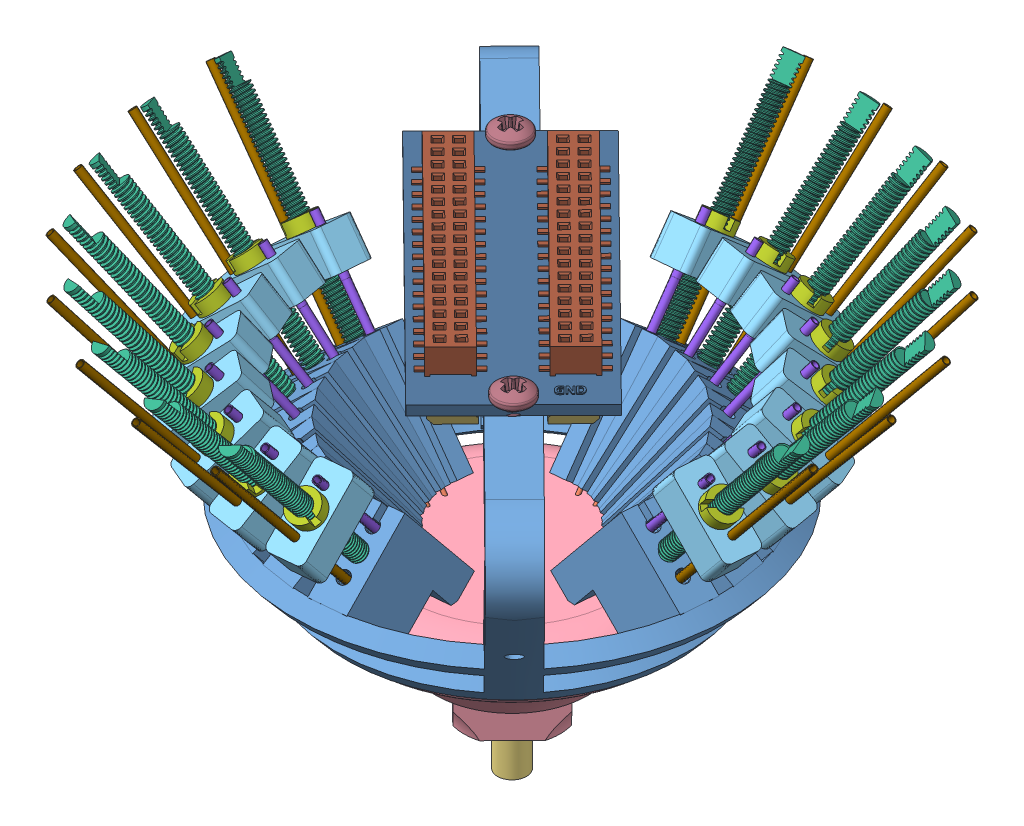
SolidWorks assembly DriveAssembly-Omnetics, configuration Default. Lengths in mm.
Overall size (57.17 40.07 57.14).
123 component instances, 13 part files, 92 mates.
Components (placement in the parent):
- drive_circle_16-1: drive_circle_16 [Default] at (0.6579 7.146 2.7452) x (0.996757 0 0.080473) z (-0.080473 0 0.996757) size (47.61 33.72 39.95)
- 30g Tubing Curved-1: 30g Tubing Curved [Default] at (-0.3006 6 2.6678) x (0.996757 0 0.080473) z (-0.080473 0 0.996757) size (13.26 23.81 0.32)
- 30g Tubing Curved-5: 30g Tubing Curved [Default] at (-0.29 6 2.9067) x (0.985792 0 -0.167972) z (0.167972 0 0.985792) size (13.26 23.81 0.32)
- 30g Tubing Curved-13: 30g Tubing Curved [Default] at (-0.2209 6 3.1356) x (0.91386 0 -0.406029) z (0.406029 0 0.91386) size (13.26 23.81 0.32)
- 30g Tubing Curved-14: 30g Tubing Curved [Default] at (-0.0973 6 3.3404) x (0.78541 0 -0.618976) z (0.618976 0 0.78541) size (13.26 23.81 0.32)
- 30g Tubing Curved-15: 30g Tubing Curved [Default] at (0.0729 6 3.5084) x (0.608386 0 -0.793641) z (0.793641 0 0.608386) size (13.26 23.81 0.32)
- 30g Tubing Curved-16: 30g Tubing Curved [Default] at (0.2793 6 3.6291) x (0.393737 0 -0.919223) z (0.919223 0 0.393737) size (13.26 23.81 0.32)
- 30g Tubing Curved-17: 30g Tubing Curved [Default] at (0.5091 6 3.6952) x (0.154736 0 -0.987956) z (0.987956 0 0.154736) size (13.26 23.81 0.32)
- 30g Tubing Curved-18: 30g Tubing Curved [Default] at (0.7481 6 3.7026) x (-0.093834 0 -0.995588) z (0.995588 0 -0.093834) size (13.26 23.81 0.32)
- 30g Tubing Curved-27: 30g Tubing Curved [Default] at (1.6164 6 2.8226) x (-0.996757 0 -0.080473) z (0.080473 0 -0.996757) size (13.26 23.81 0.32)
- 30g Tubing Curved-28: 30g Tubing Curved [Default] at (1.6059 6 2.5837) x (-0.985792 0 0.167972) z (-0.167972 0 -0.985792) size (13.26 23.81 0.32)
- 30g Tubing Curved-29: 30g Tubing Curved [Default] at (1.5367 6 2.3548) x (-0.91386 0 0.406029) z (-0.406029 0 -0.91386) size (13.26 23.81 0.32)
- 30g Tubing Curved-30: 30g Tubing Curved [Default] at (1.4132 6 2.15) x (-0.78541 0 0.618976) z (-0.618976 0 -0.78541) size (13.26 23.81 0.32)
- 30g Tubing Curved-31: 30g Tubing Curved [Default] at (1.2429 6 1.982) x (-0.608386 0 0.793641) z (-0.793641 0 -0.608386) size (13.26 23.81 0.32)
- 30g Tubing Curved-34: 30g Tubing Curved [Default] at (1.0365 6 1.8613) x (-0.393737 0 0.919223) z (-0.919223 0 -0.393737) size (13.26 23.81 0.32)
- 30g Tubing Curved-35: 30g Tubing Curved [Default] at (0.8067 6 1.7952) x (-0.154736 0 0.987956) z (-0.987956 0 -0.154736) size (13.26 23.81 0.32)
- 30g Tubing Curved-36: 30g Tubing Curved [Default] at (0.5677 6 1.7878) x (0.093834 0 0.995588) z (-0.995588 0 0.093834) size (13.26 23.81 0.32)
- MainCanula-1: MainCanula [Default] at (0.6579 0 2.7452) x (-0.437751 0 0.899096) z (-0.899096 0 -0.437751) size (2.41 8 2.41)
- AcrylicFill-1: AcrylicFill [Default] at (0.6579 2.4564 2.7452) x (0.711833 0 0.702349) z (-0.702349 0 0.711833) size (25 12 25)
- Shuttle Assembly-18: Shuttle Assembly [Default] at (17.6138 21.248 9.6542) x (-0.76356 0.642788 -0.061646) z (0.080473 0 -0.996757) size (6.5 25.22 3.31)
  - Shuttle-1: Shuttle [Default] at (2.5582 1.9761 5.5221) size (6.5 3 3)
  - Threaded Rod 25mm-1: Threaded Rod 25mm [Default] at (2.5582 -8.5786 5.5221) x (0.813094 0 0.582132) z (-0.582132 0 0.813094) size (1.64 25.22 1.64)
  - Grooved Nut-1: Grooved Nut [Default] at (2.5582 1.9761 5.5221) x (0.414361 0 -0.910113) z (0.910113 0 0.414361) size (2.5 4 2.5)
  - 23g Tubing 13mm-1: 23g Tubing 13mm [Default] at (4.3082 -7.0239 5.5221) size (0.64 13 0.64)
  - 23g Tubing 25mm-1: 23g Tubing 25mm [Default] at (0.8082 -8.5786 5.5221) size (0.62 25 0.62)
- Shuttle Assembly-19: Shuttle Assembly [Default] at (18.7944 21.248 5.2566) x (-0.75516 0.642788 0.128674) z (-0.167972 0 -0.985792) size (6.5 25.22 3.31)
  - Shuttle-1: Shuttle [Default] at (2.5582 1.9761 5.5221) size (6.5 3 3)
  - Threaded Rod 25mm-1: Threaded Rod 25mm [Default] at (2.5582 -8.5786 5.5221) x (0.813094 0 0.582132) z (-0.582132 0 0.813094) size (1.64 25.22 1.64)
  - Grooved Nut-1: Grooved Nut [Default] at (2.5582 1.9761 5.5221) x (0.414361 0 -0.910113) z (0.910113 0 0.414361) size (2.5 4 2.5)
  - 23g Tubing 13mm-1: 23g Tubing 13mm [Default] at (4.3082 -7.0239 5.5221) size (0.64 13 0.64)
  - 23g Tubing 25mm-1: 23g Tubing 25mm [Default] at (0.8082 -8.5786 5.5221) size (0.62 25 0.62)
- Shuttle Assembly-20: Shuttle Assembly [Default] at (18.8532 21.248 0.7036) x (-0.700057 0.642788 0.311037) z (-0.406029 0 -0.91386) size (6.5 25.22 3.31)
  - Shuttle-1: Shuttle [Default] at (2.5582 1.9761 5.5221) size (6.5 3 3)
  - Threaded Rod 25mm-1: Threaded Rod 25mm [Default] at (2.5582 -8.5786 5.5221) x (0.813094 0 0.582132) z (-0.582132 0 0.813094) size (1.64 25.22 1.64)
  - Grooved Nut-1: Grooved Nut [Default] at (2.5582 1.9761 5.5221) x (0.414361 0 -0.910113) z (0.910113 0 0.414361) size (2.5 4 2.5)
  - 23g Tubing 13mm-1: 23g Tubing 13mm [Default] at (4.3082 -7.0239 5.5221) size (0.64 13 0.64)
  - 23g Tubing 25mm-1: 23g Tubing 25mm [Default] at (0.8082 -8.5786 5.5221) size (0.62 25 0.62)
- Shuttle Assembly-21: Shuttle Assembly [Default] at (17.7868 21.248 -3.7231) x (-0.601659 0.642788 0.474163) z (-0.618976 0 -0.78541) size (6.5 25.22 3.31)
  - Shuttle-1: Shuttle [Default] at (2.5582 1.9761 5.5221) size (6.5 3 3)
  - Threaded Rod 25mm-1: Threaded Rod 25mm [Default] at (2.5582 -8.5786 5.5221) x (0.813094 0 0.582132) z (-0.582132 0 0.813094) size (1.64 25.22 1.64)
  - Grooved Nut-1: Grooved Nut [Default] at (2.5582 1.9761 5.5221) x (0.414361 0 -0.910113) z (0.910113 0 0.414361) size (2.5 4 2.5)
  - 23g Tubing 13mm-1: 23g Tubing 13mm [Default] at (4.3082 -7.0239 5.5221) size (0.64 13 0.64)
  - 23g Tubing 25mm-1: 23g Tubing 25mm [Default] at (0.8082 -8.5786 5.5221) size (0.62 25 0.62)
- Shuttle Assembly-22: Shuttle Assembly [Default] at (15.6611 21.248 -7.7497) x (-0.466051 0.642788 0.607964) z (-0.793641 0 -0.608386) size (6.5 25.22 3.31)
  - Shuttle-1: Shuttle [Default] at (2.5582 1.9761 5.5221) size (6.5 3 3)
  - Threaded Rod 25mm-1: Threaded Rod 25mm [Default] at (2.5582 -8.5786 5.5221) x (0.813094 0 0.582132) z (-0.582132 0 0.813094) size (1.64 25.22 1.64)
  - Grooved Nut-1: Grooved Nut [Default] at (2.5582 1.9761 5.5221) x (0.414361 0 -0.910113) z (0.910113 0 0.414361) size (2.5 4 2.5)
  - 23g Tubing 13mm-1: 23g Tubing 13mm [Default] at (4.3082 -7.0239 5.5221) size (0.64 13 0.64)
  - 23g Tubing 25mm-1: 23g Tubing 25mm [Default] at (0.8082 -8.5786 5.5221) size (0.62 25 0.62)
- Shuttle Assembly-23: Shuttle Assembly [Default] at (12.6074 21.248 -11.1273) x (-0.30162 0.642788 0.704166) z (-0.919223 0 -0.393737) size (6.5 25.22 3.31)
  - Shuttle-1: Shuttle [Default] at (2.5582 1.9761 5.5221) size (6.5 3 3)
  - Threaded Rod 25mm-1: Threaded Rod 25mm [Default] at (2.5582 -8.5786 5.5221) x (0.813094 0 0.582132) z (-0.582132 0 0.813094) size (1.64 25.22 1.64)
  - Grooved Nut-1: Grooved Nut [Default] at (2.5582 1.9761 5.5221) x (0.414361 0 -0.910113) z (0.910113 0 0.414361) size (2.5 4 2.5)
  - 23g Tubing 13mm-1: 23g Tubing 13mm [Default] at (4.3082 -7.0239 5.5221) size (0.64 13 0.64)
  - 23g Tubing 25mm-1: 23g Tubing 25mm [Default] at (0.8082 -8.5786 5.5221) size (0.62 25 0.62)
- Shuttle Assembly-24: Shuttle Assembly [Default] at (8.8148 21.248 -13.647) x (-0.118535 0.642788 0.756818) z (-0.987956 0 -0.154736) size (6.5 25.22 3.31)
  - Shuttle-1: Shuttle [Default] at (2.5582 1.9761 5.5221) size (6.5 3 3)
  - Threaded Rod 25mm-1: Threaded Rod 25mm [Default] at (2.5582 -8.5786 5.5221) x (0.813094 0 0.582132) z (-0.582132 0 0.813094) size (1.64 25.22 1.64)
  - Grooved Nut-1: Grooved Nut [Default] at (2.5582 1.9761 5.5221) x (0.414361 0 -0.910113) z (0.910113 0 0.414361) size (2.5 4 2.5)
  - 23g Tubing 13mm-1: 23g Tubing 13mm [Default] at (4.3082 -7.0239 5.5221) size (0.64 13 0.64)
  - 23g Tubing 25mm-1: 23g Tubing 25mm [Default] at (0.8082 -8.5786 5.5221) size (0.62 25 0.62)
- Shuttle Assembly-25: Shuttle Assembly [Default] at (4.5176 21.248 -15.1528) x (0.071881 0.642788 0.762665) z (-0.995588 0 0.093834) size (6.5 25.22 3.31)
  - Shuttle-1: Shuttle [Default] at (2.5582 1.9761 5.5221) size (6.5 3 3)
  - Threaded Rod 25mm-1: Threaded Rod 25mm [Default] at (2.5582 -8.5786 5.5221) x (0.813094 0 0.582132) z (-0.582132 0 0.813094) size (1.64 25.22 1.64)
  - Grooved Nut-1: Grooved Nut [Default] at (2.5582 1.9761 5.5221) x (0.414361 0 -0.910113) z (0.910113 0 0.414361) size (2.5 4 2.5)
  - 23g Tubing 13mm-1: 23g Tubing 13mm [Default] at (4.3082 -7.0239 5.5221) size (0.64 13 0.64)
  - 23g Tubing 25mm-1: 23g Tubing 25mm [Default] at (0.8082 -8.5786 5.5221) size (0.62 25 0.62)
- Shuttle Assembly-26: Shuttle Assembly [Default] at (-16.298 21.248 -4.1638) x (0.76356 0.642788 0.061646) z (-0.080473 0 0.996757) size (6.5 25.22 3.31)
  - Shuttle-1: Shuttle [Default] at (2.5582 1.9761 5.5221) size (6.5 3 3)
  - Threaded Rod 25mm-1: Threaded Rod 25mm [Default] at (2.5582 -8.5786 5.5221) x (0.813094 0 0.582132) z (-0.582132 0 0.813094) size (1.64 25.22 1.64)
  - Grooved Nut-1: Grooved Nut [Default] at (2.5582 1.9761 5.5221) x (0.414361 0 -0.910113) z (0.910113 0 0.414361) size (2.5 4 2.5)
  - 23g Tubing 13mm-1: 23g Tubing 13mm [Default] at (4.3082 -7.0239 5.5221) size (0.64 13 0.64)
  - 23g Tubing 25mm-1: 23g Tubing 25mm [Default] at (0.8082 -8.5786 5.5221) size (0.62 25 0.62)
- Shuttle Assembly-27: Shuttle Assembly [Default] at (-17.4785 21.248 0.2338) x (0.75516 0.642788 -0.128674) z (0.167972 0 0.985792) size (6.5 25.22 3.31)
  - Shuttle-1: Shuttle [Default] at (2.5582 1.9761 5.5221) size (6.5 3 3)
  - Threaded Rod 25mm-1: Threaded Rod 25mm [Default] at (2.5582 -8.5786 5.5221) x (0.813094 0 0.582132) z (-0.582132 0 0.813094) size (1.64 25.22 1.64)
  - Grooved Nut-1: Grooved Nut [Default] at (2.5582 1.9761 5.5221) x (0.414361 0 -0.910113) z (0.910113 0 0.414361) size (2.5 4 2.5)
  - 23g Tubing 13mm-1: 23g Tubing 13mm [Default] at (4.3082 -7.0239 5.5221) size (0.64 13 0.64)
  - 23g Tubing 25mm-1: 23g Tubing 25mm [Default] at (0.8082 -8.5786 5.5221) size (0.62 25 0.62)
- Shuttle Assembly-28: Shuttle Assembly [Default] at (-17.5374 21.248 4.7868) x (0.700057 0.642788 -0.311037) z (0.406029 0 0.91386) size (6.5 25.22 3.31)
  - Shuttle-1: Shuttle [Default] at (2.5582 1.9761 5.5221) size (6.5 3 3)
  - Threaded Rod 25mm-1: Threaded Rod 25mm [Default] at (2.5582 -8.5786 5.5221) x (0.813094 0 0.582132) z (-0.582132 0 0.813094) size (1.64 25.22 1.64)
  - Grooved Nut-1: Grooved Nut [Default] at (2.5582 1.9761 5.5221) x (0.414361 0 -0.910113) z (0.910113 0 0.414361) size (2.5 4 2.5)
  - 23g Tubing 13mm-1: 23g Tubing 13mm [Default] at (4.3082 -7.0239 5.5221) size (0.64 13 0.64)
  - 23g Tubing 25mm-1: 23g Tubing 25mm [Default] at (0.8082 -8.5786 5.5221) size (0.62 25 0.62)
- Shuttle Assembly-29: Shuttle Assembly [Default] at (-16.471 21.248 9.2134) x (0.601659 0.642788 -0.474163) z (0.618976 0 0.78541) size (6.5 25.22 3.31)
  - Shuttle-1: Shuttle [Default] at (2.5582 1.9761 5.5221) size (6.5 3 3)
  - Threaded Rod 25mm-1: Threaded Rod 25mm [Default] at (2.5582 -8.5786 5.5221) x (0.813094 0 0.582132) z (-0.582132 0 0.813094) size (1.64 25.22 1.64)
  - Grooved Nut-1: Grooved Nut [Default] at (2.5582 1.9761 5.5221) x (0.414361 0 -0.910113) z (0.910113 0 0.414361) size (2.5 4 2.5)
  - 23g Tubing 13mm-1: 23g Tubing 13mm [Default] at (4.3082 -7.0239 5.5221) size (0.64 13 0.64)
  - 23g Tubing 25mm-1: 23g Tubing 25mm [Default] at (0.8082 -8.5786 5.5221) size (0.62 25 0.62)
- Shuttle Assembly-30: Shuttle Assembly [Default] at (-14.3452 21.248 13.2401) x (0.466051 0.642788 -0.607964) z (0.793641 0 0.608386) size (6.5 25.22 3.31)
  - Shuttle-1: Shuttle [Default] at (2.5582 1.9761 5.5221) size (6.5 3 3)
  - Threaded Rod 25mm-1: Threaded Rod 25mm [Default] at (2.5582 -8.5786 5.5221) x (0.813094 0 0.582132) z (-0.582132 0 0.813094) size (1.64 25.22 1.64)
  - Grooved Nut-1: Grooved Nut [Default] at (2.5582 1.9761 5.5221) x (0.414361 0 -0.910113) z (0.910113 0 0.414361) size (2.5 4 2.5)
  - 23g Tubing 13mm-1: 23g Tubing 13mm [Default] at (4.3082 -7.0239 5.5221) size (0.64 13 0.64)
  - 23g Tubing 25mm-1: 23g Tubing 25mm [Default] at (0.8082 -8.5786 5.5221) size (0.62 25 0.62)
- Shuttle Assembly-32: Shuttle Assembly [Default] at (-11.2916 21.248 16.6177) x (0.30162 0.642788 -0.704166) z (0.919223 0 0.393737) size (6.5 25.22 3.31)
  - Shuttle-1: Shuttle [Default] at (2.5582 1.9761 5.5221) size (6.5 3 3)
  - Threaded Rod 25mm-1: Threaded Rod 25mm [Default] at (2.5582 -8.5786 5.5221) x (0.813094 0 0.582132) z (-0.582132 0 0.813094) size (1.64 25.22 1.64)
  - Grooved Nut-1: Grooved Nut [Default] at (2.5582 1.9761 5.5221) x (0.414361 0 -0.910113) z (0.910113 0 0.414361) size (2.5 4 2.5)
  - 23g Tubing 13mm-1: 23g Tubing 13mm [Default] at (4.3082 -7.0239 5.5221) size (0.64 13 0.64)
  - 23g Tubing 25mm-1: 23g Tubing 25mm [Default] at (0.8082 -8.5786 5.5221) size (0.62 25 0.62)
- Shuttle Assembly-33: Shuttle Assembly [Default] at (-7.4989 21.248 19.1374) x (0.118535 0.642788 -0.756818) z (0.987956 0 0.154736) size (6.5 25.22 3.31)
  - Shuttle-1: Shuttle [Default] at (2.5582 1.9761 5.5221) size (6.5 3 3)
  - Threaded Rod 25mm-1: Threaded Rod 25mm [Default] at (2.5582 -8.5786 5.5221) x (0.813094 0 0.582132) z (-0.582132 0 0.813094) size (1.64 25.22 1.64)
  - Grooved Nut-1: Grooved Nut [Default] at (2.5582 1.9761 5.5221) x (0.414361 0 -0.910113) z (0.910113 0 0.414361) size (2.5 4 2.5)
  - 23g Tubing 13mm-1: 23g Tubing 13mm [Default] at (4.3082 -7.0239 5.5221) size (0.64 13 0.64)
  - 23g Tubing 25mm-1: 23g Tubing 25mm [Default] at (0.8082 -8.5786 5.5221) size (0.62 25 0.62)
- Shuttle Assembly-34: Shuttle Assembly [Default] at (-3.2018 21.248 20.6432) x (-0.071881 0.642788 -0.762665) z (0.995588 0 -0.093834) size (6.5 25.22 3.31)
  - Shuttle-1: Shuttle [Default] at (2.5582 1.9761 5.5221) size (6.5 3 3)
  - Threaded Rod 25mm-1: Threaded Rod 25mm [Default] at (2.5582 -8.5786 5.5221) x (0.813094 0 0.582132) z (-0.582132 0 0.813094) size (1.64 25.22 1.64)
  - Grooved Nut-1: Grooved Nut [Default] at (2.5582 1.9761 5.5221) x (0.414361 0 -0.910113) z (0.910113 0 0.414361) size (2.5 4 2.5)
  - 23g Tubing 13mm-1: 23g Tubing 13mm [Default] at (4.3082 -7.0239 5.5221) size (0.64 13 0.64)
  - 23g Tubing 25mm-1: 23g Tubing 25mm [Default] at (0.8082 -8.5786 5.5221) size (0.62 25 0.62)
- EIB_millmax-1: EIB_millmax [Default] at (0.6579 33.2883 2.7452) x (0.711833 0 0.702349) z (-0.702349 0 0.711833) size (27.94 8.65 12.7)
  - EIB_millmax_PCB-1: EIB_millmax_PCB [Default] at origin size (27.94 0.9 12.7)
  - Samtec-CLP-117-02-L-D-1: Samtec-CLP-117-02-L-D [LEAD STYLE2PINS17PLATINGLROWD] at (0.2159 0.927 3.691) size (22.02 4.09 4.6)
  - Samtec-CLP-117-02-L-D-3: Samtec-CLP-117-02-L-D [LEAD STYLE2PINS17PLATINGLROWD] at (0.2159 0.927 -3.691) size (22.02 4.09 4.6)
  - Samtec-CLP-116-02-L-DH-1: Samtec-CLP-116-02-L-DH [LEAD STYLE2PINS16PLATINGLROWDH] at (-0.4191 -1.7145 -2.04) x (1 0 0) z (0 1 0) size (20.75 4.57 4.32)
  - Samtec-CLP-116-02-L-DH-2: Samtec-CLP-116-02-L-DH [LEAD STYLE2PINS16PLATINGLROWDH] at (-0.4191 -1.7145 2.04) x (-1 0 0) z (0 1 0) size (20.75 4.57 4.32)
- McMasterCarr_0-80_91772A052-1: McMasterCarr_0-80_91772A052 [91772A052] at (-8.8344 30.9133 -6.6206) x (1 0 0) z (0 1 0) size (2.95 2.95 6.38)
- McMasterCarr_0-80_91772A052-2: McMasterCarr_0-80_91772A052 [91772A052] at (10.1502 30.9133 12.111) x (1 0 0) z (0 1 0) size (2.95 2.95 6.38)
Mates (geometry in assembly coordinates):
- Concentric1: concentric aligned: circle of drive_circle_16-1; circle of 30g Tubing Curved-1
- Concentric5: concentric aligned: circle of 30g Tubing Curved-5; circle of drive_circle_16-1
- Concentric6: concentric aligned: circle of 30g Tubing Curved-13; circle of drive_circle_16-1
- Concentric7: concentric aligned: circle of 30g Tubing Curved-14; circle of drive_circle_16-1
- Concentric8: concentric aligned: circle of 30g Tubing Curved-15; circle of drive_circle_16-1
- Concentric9: concentric aligned: circle of 30g Tubing Curved-16; circle of drive_circle_16-1
- Concentric10: concentric aligned: circle of 30g Tubing Curved-17; circle of drive_circle_16-1
- Concentric11: concentric aligned: circle of 30g Tubing Curved-18; circle of drive_circle_16-1
- Parallel1: parallel anti-aligned: plane of 30g Tubing Curved-5 through (-0.0929 -2 2.8731) normal (0 -1 0); plane of assembly through (0 0 0) normal (0 1 0)
- Parallel2: parallel anti-aligned: plane of 30g Tubing Curved-1 through (-0.1012 -2 2.6839) normal (0 -1 0); plane of assembly through (0 0 0) normal (0 1 0)
- Parallel3: parallel anti-aligned: plane of 30g Tubing Curved-18 through (0.7294 -2 3.5035) normal (0 -1 0); plane of assembly through (0 0 0) normal (0 1 0)
- Parallel4: parallel anti-aligned: plane of 30g Tubing Curved-17 through (0.5401 -2 3.4976) normal (0 -1 0); plane of assembly through (0 0 0) normal (0 1 0)
- Parallel5: parallel anti-aligned: plane of 30g Tubing Curved-16 through (0.358 -2 3.4453) normal (0 -1 0); plane of assembly through (0 0 0) normal (0 1 0)
- Parallel6: parallel anti-aligned: plane of 30g Tubing Curved-15 through (0.1946 -2 3.3496) normal (0 -1 0); plane of assembly through (0 0 0) normal (0 1 0)
- Parallel7: parallel anti-aligned: plane of 30g Tubing Curved-14 through (0.0597 -2 3.2166) normal (0 -1 0); plane of assembly through (0 0 0) normal (0 1 0)
- Parallel8: parallel anti-aligned: plane of 30g Tubing Curved-13 through (-0.0381 -2 3.0544) normal (0 -1 0); plane of assembly through (0 0 0) normal (0 1 0)
- Distance9: distance = 0 mm aligned: plane of 30g Tubing Curved-1 through (-0.1012 -2 2.6839) normal (0 -1 0); plane of MainCanula-1 through (0.6579 -2 2.7452) normal (0 -1 0)
- Concentric12: concentric aligned: line of drive_circle_16-1 through (0.6579 7.146 2.7452) axis (0 1 0); circle of MainCanula-1
- Parallel11: parallel anti-aligned: plane of MainCanula-1 through (0.6579 6 2.7452) normal (0 1 0); plane of AcrylicFill-1 through (0.6579 2.4564 2.7452) normal (0 -1 0)
- Concentric13: concentric aligned: circle of AcrylicFill-1; circle of MainCanula-1
- StabilizerAndDriveConcentric: concentric aligned: circle of drive_circle_16-1; circle of Shuttle Assembly-18/23g Tubing 25mm-1
- BrassNutAndDriveConcentric: concentric anti-aligned: circle of drive_circle_16-1; circle of Shuttle Assembly-18/Grooved Nut-1
- ShuttleHeight: distance = 7 mm aligned: plane of Shuttle Assembly-18/Shuttle-1 through (19.2931 26.7043 4.2497) normal (0.640703 0.766044 0.051727); plane of drive_circle_16-1 through (12.4473 23.4311 2.1921) normal (0.640703 0.766044 0.051727)
- Concentric36: concentric aligned: circle of Shuttle Assembly-19/23g Tubing 25mm-1; circle of drive_circle_16-1
- Concentric37: concentric anti-aligned: circle of Shuttle Assembly-19/Grooved Nut-1; circle of drive_circle_16-1
- Distance11: distance = 7 mm aligned: plane of Shuttle Assembly-19/Shuttle-1 through (19.0881 26.7043 -0.3952) normal (0.633655 0.766044 -0.10797); plane of drive_circle_16-1 through (11.9463 23.4311 -0.6999) normal (0.633655 0.766044 -0.10797)
- Concentric38: concentric aligned: circle of Shuttle Assembly-20/23g Tubing 25mm-1; circle of drive_circle_16-1
- Concentric39: concentric anti-aligned: circle of Shuttle Assembly-20/Grooved Nut-1; circle of drive_circle_16-1
- Distance12: distance = 7 mm aligned: plane of Shuttle Assembly-20/Shuttle-1 through (17.7433 26.7043 -4.8459) normal (0.587418 0.766044 -0.260991); plane of drive_circle_16-1 through (10.7471 23.4311 -3.3788) normal (0.587418 0.766044 -0.260991)
- Concentric40: concentric aligned: circle of drive_circle_16-1; circle of Shuttle Assembly-21/23g Tubing 25mm-1
- Concentric41: concentric anti-aligned: circle of drive_circle_16-1; circle of Shuttle Assembly-21/Grooved Nut-1
- Distance13: distance = 7 mm aligned: plane of Shuttle Assembly-21/Shuttle-1 through (15.3418 26.7043 -8.8271) normal (0.504852 0.766044 -0.39787); plane of drive_circle_16-1 through (8.924 23.4311 -5.6791) normal (0.504852 0.766044 -0.39787)
- Concentric42: concentric aligned: circle of drive_circle_16-1; circle of Shuttle Assembly-22/23g Tubing 25mm-1
- Concentric43: concentric anti-aligned: circle of drive_circle_16-1; circle of Shuttle Assembly-22/Grooved Nut-1
- Distance14: distance = 7 mm aligned: plane of Shuttle Assembly-22/Shuttle-1 through (12.0322 26.7043 -12.0926) normal (0.391063 0.766044 -0.510143); plane of drive_circle_16-1 through (6.5896 23.4311 -7.4583) normal (0.391063 0.766044 -0.510143)
- Concentric44: concentric aligned: circle of drive_circle_16-1; circle of Shuttle Assembly-23/23g Tubing 25mm-1
- Concentric45: concentric anti-aligned: circle of drive_circle_16-1; circle of Shuttle Assembly-23/Grooved Nut-1
- Distance15: distance = 7 mm aligned: plane of Shuttle Assembly-23/Shuttle-1 through (8.0192 26.7043 -14.4405) normal (0.253089 0.766044 -0.590865); plane of drive_circle_16-1 through (3.8884 23.4311 -8.6065) normal (0.253089 0.766044 -0.590865)
- Concentric46: concentric aligned: circle of drive_circle_16-1; circle of Shuttle Assembly-24/23g Tubing 25mm-1
- Concentric47: concentric anti-aligned: circle of drive_circle_16-1; circle of Shuttle Assembly-24/Grooved Nut-1
- Distance16: distance = 7 mm aligned: plane of Shuttle Assembly-24/Shuttle-1 through (3.5508 26.7043 -15.7255) normal (0.099463 0.766044 -0.635046); plane of drive_circle_16-1 through (0.9874 23.4311 -9.0526) normal (0.099463 0.766044 -0.635046)
- Concentric48: concentric aligned: circle of drive_circle_16-1; circle of Shuttle Assembly-25/23g Tubing 25mm-1
- Concentric49: concentric anti-aligned: circle of drive_circle_16-1; circle of Shuttle Assembly-25/Grooved Nut-1
- Distance17: distance = 7 mm aligned: plane of Shuttle Assembly-25/Shuttle-1 through (-1.0964 26.7043 -15.8682) normal (-0.060315 0.766044 -0.639952); plane of drive_circle_16-1 through (-1.934 23.4311 -8.7691) normal (-0.060315 0.766044 -0.639952)
- Concentric50: concentric anti-aligned: circle of drive_circle_16-1; circle of Shuttle Assembly-26/23g Tubing 25mm-1
- Concentric51: concentric aligned: circle of drive_circle_16-1; circle of Shuttle Assembly-26/Grooved Nut-1
- Distance18: distance = 7 mm aligned: plane of Shuttle Assembly-26/Shuttle-1 through (-17.9773 26.7043 1.2407) normal (-0.640703 0.766044 -0.051727); plane of drive_circle_16-1 through (-10.8901 23.4311 0.308) normal (-0.640703 0.766044 -0.051727)
- Concentric52: concentric anti-aligned: circle of drive_circle_16-1; circle of Shuttle Assembly-27/23g Tubing 25mm-1
- Concentric53: concentric aligned: circle of drive_circle_16-1; circle of Shuttle Assembly-27/Grooved Nut-1
- Distance19: distance = 7 mm aligned: plane of Shuttle Assembly-27/Shuttle-1 through (-17.7723 26.7043 5.8856) normal (-0.633655 0.766044 0.10797); plane of drive_circle_16-1 through (-11.1344 23.4311 3.2329) normal (-0.633655 0.766044 0.10797)
- Concentric54: concentric anti-aligned: circle of drive_circle_16-1; circle of Shuttle Assembly-28/23g Tubing 25mm-1
- Concentric55: concentric aligned: circle of drive_circle_16-1; circle of Shuttle Assembly-28/Grooved Nut-1
- Distance20: distance = 7 mm aligned: plane of Shuttle Assembly-28/Shuttle-1 through (-16.4275 26.7043 10.3363) normal (-0.587418 0.766044 0.260991); plane of drive_circle_16-1 through (-10.6494 23.4311 6.1277) normal (-0.587418 0.766044 0.260991)
- Concentric56: concentric anti-aligned: circle of drive_circle_16-1; circle of Shuttle Assembly-29/23g Tubing 25mm-1
- Concentric57: concentric aligned: circle of drive_circle_16-1; circle of Shuttle Assembly-29/Grooved Nut-1
- Distance21: distance = 7 mm aligned: plane of Shuttle Assembly-29/Shuttle-1 through (-14.026 26.7043 14.3175) normal (-0.504852 0.766044 0.39787); plane of drive_circle_16-1 through (-9.4651 23.4311 8.8132) normal (-0.504852 0.766044 0.39787)
- Concentric58: concentric anti-aligned: circle of drive_circle_16-1; circle of Shuttle Assembly-30/23g Tubing 25mm-1
- Concentric59: concentric aligned: circle of drive_circle_16-1; circle of Shuttle Assembly-30/Grooved Nut-1
- Distance22: distance = 7 mm aligned: plane of Shuttle Assembly-30/Shuttle-1 through (-10.7164 26.7043 17.583) normal (-0.391063 0.766044 0.510143); plane of drive_circle_16-1 through (-7.6547 23.4311 11.1235) normal (-0.391063 0.766044 0.510143)
- Concentric61: concentric anti-aligned: circle of Shuttle Assembly-32/23g Tubing 25mm-1; circle of drive_circle_16-1
- Concentric62: concentric aligned: circle of Shuttle Assembly-32/Grooved Nut-1; circle of drive_circle_16-1
- Distance23: distance = 7 mm aligned: plane of Shuttle Assembly-32/Shuttle-1 through (-6.7033 26.7043 19.9309) normal (-0.253089 0.766044 0.590865); plane of drive_circle_16-1 through (-5.3303 23.4311 12.9157) normal (-0.253089 0.766044 0.590865)
- Concentric63: concentric anti-aligned: circle of drive_circle_16-1; circle of Shuttle Assembly-33/23g Tubing 25mm-1
- Concentric64: concentric aligned: circle of Shuttle Assembly-33/Grooved Nut-1; circle of drive_circle_16-1
- Distance24: distance = 7 mm aligned: plane of Shuttle Assembly-33/Shuttle-1 through (-2.235 26.7043 21.2159) normal (-0.099463 0.766044 0.635046); plane of drive_circle_16-1 through (-2.6355 23.4311 14.0788) normal (-0.099463 0.766044 0.635046)
- Concentric65: concentric anti-aligned: circle of drive_circle_16-1; circle of Shuttle Assembly-34/23g Tubing 25mm-1
- Concentric66: concentric aligned: circle of drive_circle_16-1; circle of Shuttle Assembly-34/Grooved Nut-1
- Distance25: distance = 7 mm aligned: plane of Shuttle Assembly-34/Shuttle-1 through (2.4122 26.7043 21.3586) normal (0.060315 0.766044 0.639952); plane of drive_circle_16-1 through (0.263 23.4311 14.541) normal (0.060315 0.766044 0.639952)
- Concentric67: concentric anti-aligned: circle of drive_circle_16-1; circle of 30g Tubing Curved-27
- Parallel12: parallel anti-aligned: plane of 30g Tubing Curved-27 through (1.4171 -2 2.8065) normal (0 -1 0); plane of assembly through (0 0 0) normal (0 1 0)
- Concentric68: concentric anti-aligned: circle of drive_circle_16-1; circle of 30g Tubing Curved-28
- Parallel13: parallel anti-aligned: plane of 30g Tubing Curved-28 through (1.4087 -2 2.6173) normal (0 -1 0); plane of assembly through (0 0 0) normal (0 1 0)
- Concentric69: concentric anti-aligned: circle of drive_circle_16-1; circle of 30g Tubing Curved-29
- Parallel14: parallel anti-aligned: plane of 30g Tubing Curved-29 through (1.3539 -2 2.436) normal (0 -1 0); plane of assembly through (0 0 0) normal (0 1 0)
- Concentric70: concentric anti-aligned: circle of drive_circle_16-1; circle of 30g Tubing Curved-30
- Parallel15: parallel anti-aligned: plane of 30g Tubing Curved-30 through (1.2561 -2 2.2738) normal (0 -1 0); plane of assembly through (0 0 0) normal (0 1 0)
- Concentric71: concentric anti-aligned: circle of drive_circle_16-1; circle of 30g Tubing Curved-31
- Parallel16: parallel anti-aligned: plane of 30g Tubing Curved-31 through (1.1213 -2 2.1408) normal (0 -1 0); plane of assembly through (0 0 0) normal (0 1 0)
- Parallel19: parallel anti-aligned: plane of 30g Tubing Curved-34 through (0.9578 -2 2.0451) normal (0 -1 0); plane of assembly through (0 0 0) normal (0 1 0)
- Concentric73: concentric anti-aligned: circle of drive_circle_16-1; circle of 30g Tubing Curved-34
- Concentric74: concentric anti-aligned: circle of drive_circle_16-1; circle of 30g Tubing Curved-35
- Parallel20: parallel anti-aligned: plane of 30g Tubing Curved-35 through (0.7758 -2 1.9928) normal (0 -1 0); plane of assembly through (0 0 0) normal (0 1 0)
- Concentric75: concentric anti-aligned: circle of drive_circle_16-1; circle of 30g Tubing Curved-36
- Parallel21: parallel anti-aligned: plane of 30g Tubing Curved-36 through (0.5864 -2 1.9869) normal (0 -1 0); plane of assembly through (0 0 0) normal (0 1 0)
- Concentric77: concentric aligned: circle of drive_circle_16-1; circle of EIB_millmax-1/EIB_millmax_PCB-1
- Concentric79: concentric aligned: circle of drive_circle_16-1; circle of EIB_millmax-1/EIB_millmax_PCB-1
- Coincident34: coincident anti-aligned: plane of drive_circle_16-1 through (-22.6906 33.2883 -17.8338) normal (0 1 0); plane of EIB_millmax-1/EIB_millmax_PCB-1 through (0.6579 33.2883 2.7452) normal (0 -1 0)
- Concentric80: concentric anti-aligned: circle of EIB_millmax-1/EIB_millmax_PCB-1; circle of McMasterCarr_0-80_91772A052-1
- Coincident35: coincident anti-aligned: plane of EIB_millmax-1/EIB_millmax_PCB-1 through (0.6579 34.0883 2.7452) normal (0 1 0); plane of McMasterCarr_0-80_91772A052-1 through (-8.8344 34.0883 -6.6206) normal (0 -1 0)
- Concentric81: concentric anti-aligned: circle of EIB_millmax-1/EIB_millmax_PCB-1; circle of McMasterCarr_0-80_91772A052-2
- Coincident36: coincident anti-aligned: plane of EIB_millmax-1/EIB_millmax_PCB-1 through (0.6579 34.0883 2.7452) normal (0 1 0); plane of McMasterCarr_0-80_91772A052-2 through (10.1502 34.0883 12.111) normal (0 -1 0)
- Parallel23: parallel aligned: plane of AcrylicFill-1 through (5.6076 6.4564 2.712) normal (0.711833 0 0.702349); plane of EIB_millmax-1/Samtec-CLP-116-02-L-DH-1 through (11.319 29.8593 6.1165) normal (0.711833 0 0.702349)
